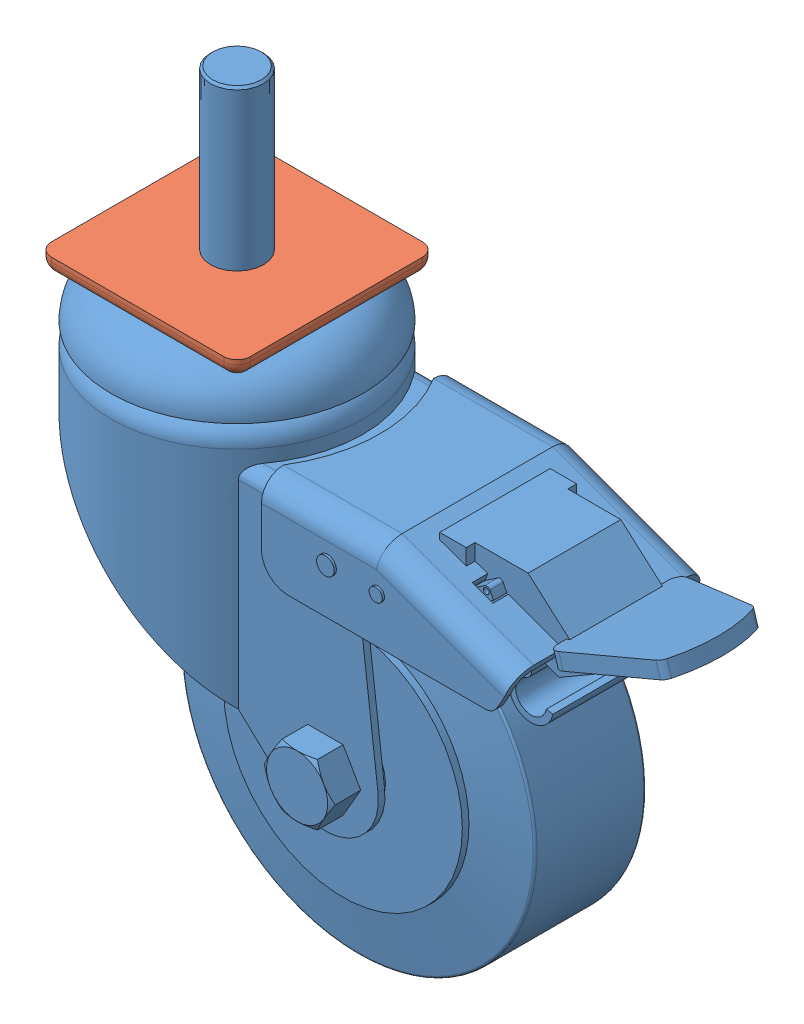
SolidWorks assembly Perna, configuration Default. Lengths in mm.
Overall size (138.5 705 57).
3 component instances, 3 part files, 4 mates.
Components (placement in the parent):
- Roda-1: Roda [Default] at origin size (138.5 148 57)
- Perfil45_593-1: Perfil45_593 [Default] at (0 4 0) x (1 0 0) z (0 -1 0) size (45 45 593)
- Tampa-2: Tampa [Default] at (0 4 0) x (1 0 0) z (0 -1 0) size (45.64 46.27 5.14)
Mates (geometry in assembly coordinates):
- Coincident4: coincident anti-aligned: plane of Perfil45_593-1 through (7.7309 4 -0.013) normal (0 -1 0); plane of Tampa-2 through (0 4 0) normal (0 1 0)
- Coincident7: coordinate: point of Perfil45_593-1; point of Tampa-2
- Coincident9: coincident anti-aligned: plane of Roda-1 through (0 0 0) normal (0 1 0); plane of Tampa-2 through (0 0 0) normal (0 -1 0)
- Concentric1: concentric: cylinder of Roda-1 through (0 42.25 0) axis (0 -1 0) radius 6; point of Tampa-2
